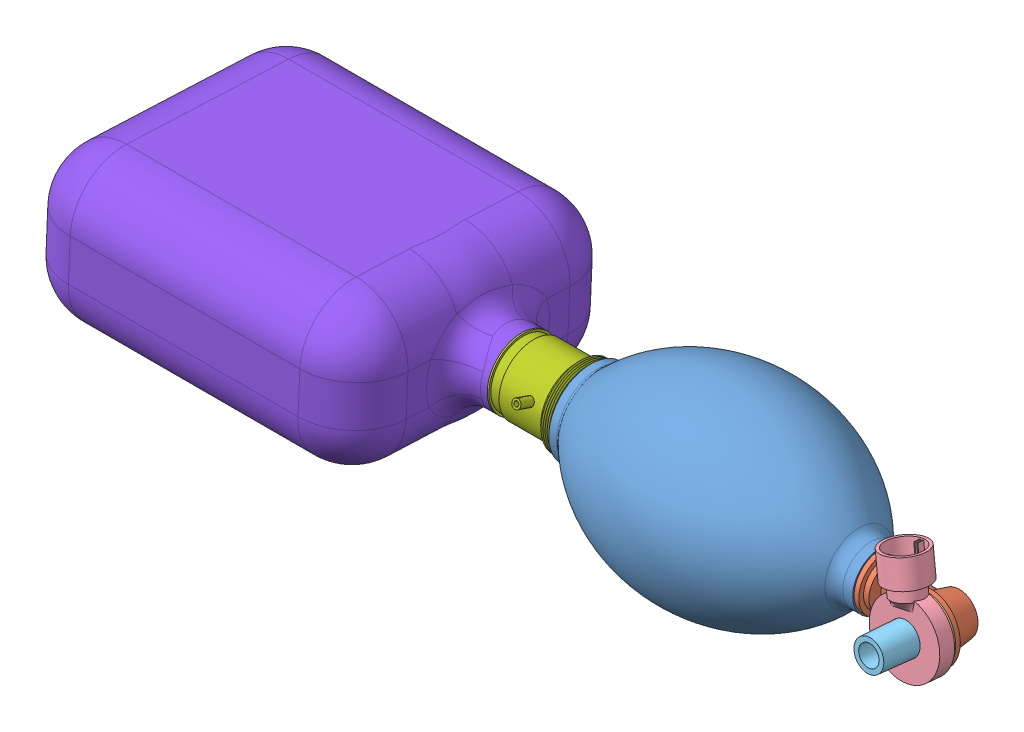
SolidWorks assembly ENSAMBLE AMBU, configuration Default. Lengths in mm.
Overall size (622.5 140 204.7).
8 component instances, 8 part files, 14 mates.
Components (placement in the parent):
- AMBU-1: AMBU [Default] at (59.0246 122.6424 167.5549) size (215 140 140)
- AMBU 2-1: AMBU 2 [Default] at (154.5246 122.6424 167.5549) x (1 0 0) z (0 -0.090693 -0.995879) size (87.96 47.5 40)
- AMBU 3-1: AMBU 3 [Default] at (218.7367 124.819 191.456) x (0.874462 -0.483094 0.043995) z (0 -0.090693 -0.995879) size (47.5 47.5 10.06)
- AMBU 4-1: AMBU 4 [Default] at (218.7367 124.547 188.4684) x (-0.201425 0.975467 -0.088834) z (0 0.090693 0.995879) size (77 52 30.5)
- AMBU 5-1: AMBU 5 [Default] at (218.7367 127.948 225.8138) x (0.415233 -0.905966 0.082505) z (0 -0.090693 -0.995879) size (32 32 35)
- AMBU 6-1: AMBU 6 [Default] at (218.7367 125.1818 195.4395) x (0.990042 0.140195 -0.012767) z (0 -0.090693 -0.995879) size (29 29 6)
- AMBU 7-1: AMBU 7 [Default] at (-40.4754 122.6424 167.5549) x (0 -0.943716 0.330756) z (-1 0 0) size (59.75 65.98 61)
- AMBU 9-1: AMBU 9 [Default] at (-121.4754 122.6424 167.5549) x (1 0 0) z (0 0.044553 0.999007) size (275 110 200)
Mates (geometry in assembly coordinates):
- Concéntrica1: concentric: cylinder of assembly; cylinder of assembly; cylinder of AMBU-1 through (-45.4754 122.6424 167.5549) axis (-1 0 0) radius 18; cylinder of AMBU 2-1 through (169.5246 122.6424 167.5549) axis (-1 0 0) radius 18
- Coincidente1: coincident: plane of assembly; plane of assembly; plane of AMBU-1 through (169.5246 122.6424 167.5549) normal (1 0 0); plane of AMBU 2-1 through (169.5246 122.6424 167.5549) normal (-1 0 0)
- Concéntrica2: concentric: cylinder of assembly; cylinder of assembly; cylinder of AMBU 3-1 through (218.7367 124.2749 185.4807) axis (0 0.090693 0.995879) radius 23.75; cylinder of AMBU 4-1 through (218.7367 125.5446 199.423) axis (0 -0.090693 -0.995879) radius 24
- Concéntrica3: concentric: cylinder of assembly; cone of assembly; cylinder of AMBU 4-1 through (218.7367 126.3608 208.3859) axis (0 -0.090693 -0.995879) radius 11.5; cone of AMBU 5-1 through (218.7367 127.948 225.8138) axis (0 0.090693 0.995879)
- Concéntrica4: concentric: cylinder of assembly; cylinder of assembly; cylinder of AMBU 2-1 through (218.7367 124.2749 185.4807) axis (0 -0.090693 -0.995879) radius 23.75; cylinder of AMBU 3-1 through (218.7367 124.2749 185.4807) axis (0 0.090693 0.995879) radius 23.75
- Concéntrica5: concentric: cone of assembly; cylinder of assembly; cone of AMBU 5-1 through (218.7367 127.948 225.8138) axis (0 0.090693 0.995879); cylinder of AMBU 6-1 through (218.7367 124.4563 187.4725) axis (0 0.090693 0.995879) radius 11.55
- Concéntrica6: concentric: cylinder of assembly; cylinder of assembly; cylinder of AMBU-1 through (-45.4754 122.6424 167.5549) axis (-1 0 0) radius 28; cylinder of AMBU 7-1 through (-96.4754 122.6424 167.5549) axis (1 0 0) radius 25.5
- Coincidente5: coincident: plane of assembly; plane of assembly; plane of AMBU 3-1 through (218.7367 124.9551 192.9498) normal (0 -0.090693 -0.995879); plane of AMBU 5-1 through (218.7367 124.9551 192.9498) normal (0 0.090693 0.995879)
- Coincidente6: coincident: plane of assembly; plane of assembly; plane of AMBU 3-1 through (218.7367 125.1818 195.4395) normal (0 0.090693 0.995879); plane of AMBU 6-1 through (218.7367 125.1818 195.4395) normal (0 -0.090693 -0.995879)
- Coincidente7: coincident: plane of assembly; plane of assembly; plane of AMBU 4-1 through (218.7367 125.3632 197.4313) normal (0 -0.090693 -0.995879); plane of AMBU 6-1 through (218.7367 125.3632 197.4313) normal (0 0.090693 0.995879)
- Coincidente8: coincident: plane of assembly; plane of assembly; plane of AMBU 2-1 through (218.7367 124.2749 185.4807) normal (0 0.090693 0.995879); plane of AMBU 3-1 through (218.7367 124.2749 185.4807) normal (0 -0.090693 -0.995879)
- Coincidente10: coincident: plane of assembly; plane of assembly; plane of AMBU-1 through (-45.4754 122.6424 167.5549) normal (-1 0 0); plane of AMBU 7-1 through (-45.4754 122.6424 167.5549) normal (1 0 0)
- Concéntrica7: concentric: cylinder of assembly; cylinder of assembly; cylinder of AMBU 7-1 through (-40.4754 122.6424 167.5549) axis (1 0 0) radius 24; cylinder of AMBU 9-1 through (-96.4754 122.6424 167.5549) axis (-1 0 0) radius 24.5
- Coincidente11: coincident: plane of assembly; plane of assembly; plane of AMBU 7-1 through (-96.4754 122.6424 167.5549) normal (-1 0 0); plane of AMBU 9-1 through (-96.4754 122.6424 167.5549) normal (1 0 0)
